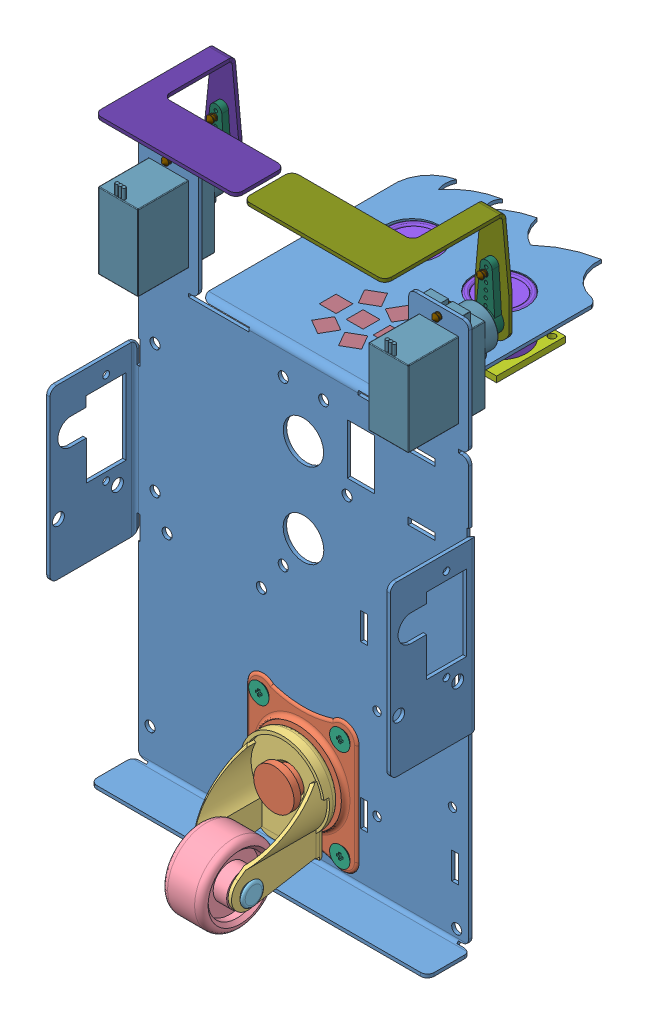
SolidWorks assembly Ensamblaje12, configuration Predeterminado. Lengths in mm.
Overall size (101.89 183.65 106.61).
42 component instances, 19 part files, 12 mates.
Components (placement in the parent):
- DYOR_LEDStrip_MetalSheet_Pusher-1: DYOR_LEDStrip_MetalSheet_Pusher [Predeterminado] at (90.4827 -137.9363 139.7994) size (101.89 161.68 94.73)
- CA-1: CA [Predeterminado] at (0.0563 -0.5 0) size (33 45.94 43.84)
  - Caster Wheel-1: Caster Wheel [Default] at (197.1109 -294.8334 184.5177) x (0 1 0) z (-1 0 0) size (45.94 37.15 33)
    - caster holder-1: caster holder [Default] at (-24.0751 44.7184 29.5137) x (1 0 0) z (0 0 -1) size (39 8.84 33)
    - holder-1: holder [Default] at (-1.5751 42.9484 46.0137) x (0 0 1) z (1 0 0) size (25 28.07 31.31)
    - caster wheel-1: caster wheel [Default] at (-15.6961 19.9484 46.0137) x (0.997275 0.073773 0) z (0 0 1) size (23 23 14)
    - Part4-1: Part4 [Default] at (-15.6961 19.9484 55.0137) x (-0.978448 0.206495 0) z (0 0 -1) size (7 7 20)
  - M4x8 SelfTap Screw-1: M4x8 SelfTap Screw [Predeterminado] at (139.0972 -281.4086 141.0494) size (6 6 8)
  - M4x8 SelfTap Screw-2: M4x8 SelfTap Screw [Predeterminado] at (163.0972 -281.4086 141.0494) size (6 6 8)
  - M4x8 SelfTap Screw-3: M4x8 SelfTap Screw [Predeterminado] at (139.0972 -311.4086 141.0494) size (6 6 8)
  - M4x8 SelfTap Screw-4: M4x8 SelfTap Screw [Predeterminado] at (163.0972 -311.4086 141.0494) size (6 6 8)
- HC-SR04 Ping Sensor-1: HC-SR04 Ping Sensor [Default] at (151.0217 -203.2073 94.6556) x (0 0 -1) z (0 1 0) size (25.18 45 18.07)
  - PCB-1: PCB [Default] at origin size (20.5 45 1.75)
  - Transducer-1: Transducer [Default] at (0 -13.16 13.25) x (1 0 0) z (0 -1 0) size (15.88 12 15.88)
  - Transducer-2: Transducer [Default] at (0 12.34 13.25) x (1 0 0) z (0 -1 0) size (15.88 12 15.88)
  - 3 Pin Header 90 Degree-1: 3 Pin Header 90 Degree [Default] at (8.4275 0 -1.25) x (-1 0 0) z (0 -1 0) size (8 7.82 10)
  - 14 Pin SMT-1: 14 Pin SMT [Default] at (-0.35 -18.5 -0.85) x (0 -1 0) z (1 0 0) size (6 1.6 8.8)
  - 14 Pin SMT-2: 14 Pin SMT [Default] at (0 -0.3826 -0.85) x (1 0 0) z (0 1 0) size (6 1.6 8.8)
  - 14 Pin SMT-3: 14 Pin SMT [Default] at (0 17.5274 -0.85) x (1 0 0) z (0 1 0) size (6 1.6 8.8)
  - Cap1 SMT-1: Cap1 SMT [Default] at (-1.755 7.4774 -0.9689) x (0 1 0) z (-1 0 0) size (4.5 1.84 1.75)
  - Cap1 SMT-2: Cap1 SMT [Default] at (6.835 7.4774 -0.9689) x (0 1 0) z (-1 0 0) size (4.5 1.84 1.75)
  - Cap1 SMT-3: Cap1 SMT [Default] at (-6.835 7.4774 -0.9689) x (0 1 0) z (-1 0 0) size (4.5 1.84 1.75)
  - Cap1 SMT-4: Cap1 SMT [Default] at (4.295 7.4774 -0.9689) x (0 1 0) z (-1 0 0) size (4.5 1.84 1.75)
  - Cap1 SMT-5: Cap1 SMT [Default] at (1.755 7.4774 -0.9689) x (0 1 0) z (-1 0 0) size (4.5 1.84 1.75)
  - Cap1 SMT-6: Cap1 SMT [Default] at (-4.295 7.4774 -0.9689) x (0 1 0) z (-1 0 0) size (4.5 1.84 1.75)
  - HC-SR04 Crystal-1: HC-SR04 Crystal [Default] at (-8.3 0 1.75) x (0 -1 0) z (0 0 1) size (10 3.5 2.7)
- ws8212-7-1: ws8212-7 [Predeterminado] at (151.1817 -192.4573 122.1556) x (0 0 -1) z (0 1 0) size (24 24 3.1)
- PU-1: PU [Predeterminado] at (-16.2421 4.6781 -1.0225) size (91.94 49.57 37.38)
  - sg90-1: sg90 [Default] at (201.5956 -166.7354 155.7219) x (0 -1 0) z (1 0 0) size (31.9 29.9 11.8)
  - sg90-2: sg90 [Default] at (121.452 -166.7354 155.7219) x (0 -1 0) z (1 0 0) size (31.9 29.9 11.8)
  - SG90 plastic Horn-1: SG90 plastic Horn [Default] at (127.352 -172.6354 127.0219) x (0.017141 0.999853 0) z (-0.999853 0.017141 0) size (19.4 4 7.07)
  - SG90 plastic Horn-2: SG90 plastic Horn [Default] at (207.4956 -172.6354 127.0219) x (0.020276 0.999794 0) z (-0.999794 0.020276 0) size (19.4 4 7.07)
  - Pusher_left-1: Pusher_left [Predeterminado] at (252.6438 -158.8738 124.0219) x (-1 0 0) z (0 0 -1) size (44 33.65 35.77)
  - Pusher_right-1: Pusher_right [Predeterminado] at (82.2037 -158.8738 125.0219) size (44 33.65 35.77)
  - M2x6 SelfTap Screw-1: M2x6 SelfTap Screw [Predeterminado] at (207.4956 -164.3354 136.8219) x (-0.923728 -0.383049 0) z (0 0 -1) size (3.4 3.28 6)
  - M2x6 SelfTap Screw-2: M2x6 SelfTap Screw [Predeterminado] at (207.4956 -191.6354 136.3219) x (-0.923728 -0.383049 0) z (0 0 -1) size (3.4 3.28 6)
  - M2x6 SelfTap Screw-3: M2x6 SelfTap Screw [Predeterminado] at (127.352 -164.3354 136.8219) x (-0.993348 0.115149 0) z (0 0 -1) size (3.4 3.28 6)
  - M2x6 SelfTap Screw-4: M2x6 SelfTap Screw [Predeterminado] at (127.352 -191.6354 136.8219) x (-0.923728 -0.383049 0) z (0 0 -1) size (3.4 3.28 6)
  - (M2_3_mm)_90116A007_METRIC 316 SS PAN HEAD PHILLIPS MACHINE SCREW-1: (M2_3_mm)_90116A007_METRIC 316 SS PAN HEAD PHILLIPS MACHINE SCREW [90116A007] at (127.352 -172.6354 127.0219) x (-0.923728 -0.383049 0) z (0 0 -1) size (4 4 4.68)
  - (M2_3_mm)_90116A007_METRIC 316 SS PAN HEAD PHILLIPS MACHINE SCREW-2: (M2_3_mm)_90116A007_METRIC 316 SS PAN HEAD PHILLIPS MACHINE SCREW [90116A007] at (207.4956 -172.6354 127.0219) x (-0.923728 -0.383049 0) z (0 0 -1) size (4 4 4.68)
  - M2x6 SelfTap Screw-5: M2x6 SelfTap Screw [Predeterminado] at (127.352 -160.1354 123.5219) x (-0.923728 -0.383049 0) z (0 0 -1) size (3.4 3.28 6)
  - M2x6 SelfTap Screw-6: M2x6 SelfTap Screw [Predeterminado] at (207.4956 -160.1354 123.5219) x (-0.923728 -0.383049 0) z (0 0 -1) size (3.4 3.28 6)
Mates (geometry in assembly coordinates):
- Coincidente524: coincident: plane of DYOR_LEDStrip_MetalSheet_Pusher-1 through (123.0098 -188.9573 139.7994) normal (0 0 1); plane of CA-1/Caster Wheel-1/caster holder-1 through (151.1535 -252.1104 139.7994) normal (0 0 -1)
- Concéntrica316: concentric: circle of DYOR_LEDStrip_MetalSheet_Pusher-1; circle of CA-1/M4x8 SelfTap Screw-2
- Concéntrica317: concentric: circle of DYOR_LEDStrip_MetalSheet_Pusher-1; circle of CA-1/M4x8 SelfTap Screw-4
- Concéntrica318: concentric: circle of DYOR_LEDStrip_MetalSheet_Pusher-1; circle of HC-SR04 Ping Sensor-1/Transducer-1
- Coincidente525: coincident: plane of DYOR_LEDStrip_MetalSheet_Pusher-1 through (123.0098 -189.4573 137.6556) normal (0 1 0); plane of HC-SR04 Ping Sensor-1/Transducer-1 through (164.1817 -189.4573 86.7156) normal (0 1 0)
- Paralelo102: parallel: plane of DYOR_LEDStrip_MetalSheet_Pusher-1 through (123.0098 -188.9573 138.7994) normal (0 0 -1); plane of HC-SR04 Ping Sensor-1/PCB-1 through (128.5217 -201.4573 104.9056) normal (0 0 1)
- Coincidente527: coincident: plane of DYOR_LEDStrip_MetalSheet_Pusher-1 through (123.0098 -188.9573 138.7994) normal (0 0 -1); plane of PU-1/sg90-1 through (197.1535 -189.2573 138.7994) normal (0 0 1)
- Concéntrica319: concentric: circle of DYOR_LEDStrip_MetalSheet_Pusher-1; circle of PU-1/M2x6 SelfTap Screw-2
- Concéntrica320: concentric: circle of DYOR_LEDStrip_MetalSheet_Pusher-1; circle of PU-1/M2x6 SelfTap Screw-1
- Coincidente528: coincident: plane of DYOR_LEDStrip_MetalSheet_Pusher-1 through (123.0098 -189.4573 137.6556) normal (0 1 0); plane of ws8212-7-1 through (151.1817 -189.4573 122.1556) normal (0 1 0)
- Coincidente529: coincident: plane of DYOR_LEDStrip_MetalSheet_Pusher-1 through (143.7666 -190.4573 114.3123) normal (0.866025 0 -0.5); plane of ws8212-7-1 through (143.7666 -189.4573 114.3123) normal (-0.866025 0 0.5)
- Coincidente530: coincident: plane of DYOR_LEDStrip_MetalSheet_Pusher-1 through (148.0967 -190.4573 111.8123) normal (0.5 0 0.866025); plane of ws8212-7-1 through (143.7666 -189.4573 114.3123) normal (-0.5 0 -0.866025)
